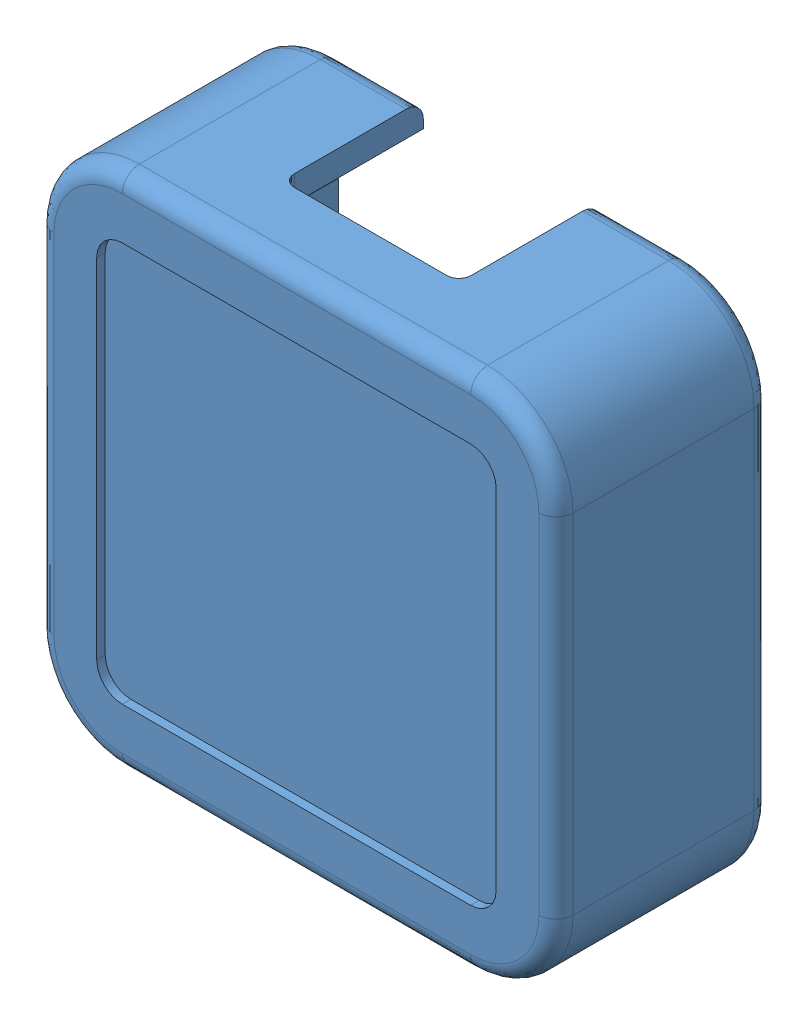
SolidWorks assembly enclosure-compatible module moulded 20x20, configuration Default. Lengths in mm.
Overall size (30.4 30.4 12.6).
5 component instances, 5 part files, 12 mates.
Components (placement in the parent):
- enclosure-compatible module 20x20-1: enclosure-compatible module 20x20 [Default] at (8.2244 14.4247 23.4545) size (27 28.5 1.62) (hidden)
- edge connector wall-1: edge connector wall [Default] at (8.2244 27.9247 23.4545) x (1 0 0) z (0 1 0) size (12.94 7.5 5.35) (hidden)
- enclosure end piece jacdac 20-1: enclosure end piece jacdac 20 [Default] at (8.2244 27.9247 23.4545) x (1 0 0) z (0 1 0) size (20 7.5 2) (hidden)
- enclosure end piece solid 20-1: enclosure end piece solid 20 [Default] at (8.2244 0.9247 25.0045) x (1 0 0) z (0 -1 0) size (20 7.5 2) (hidden)
- enclosure moulded 20x20-1: enclosure moulded 20x20 [Default] at (8.2244 27.9247 23.4545) x (1 0 0) z (0 1 0) size (30.4 12.6 30.4)
Mates (geometry in assembly coordinates):
- InPlace1: in place: plane of enclosure-compatible module 20x20-1 through (-5.2756 27.9247 25.0545) normal (0 1 0); plane of ? through (0 27.9247 0) normal (0 1 0); moOrthogonalPlaneRef_w of enclosure-compatible module 20x20-1 through (-5.2756 27.9247 25.0545) normal (0 1 0); plane of ? through (0 27.9247 0) normal (0 0 -1); plane of enclosure-compatible module 20x20-1 through (-5.2756 27.9247 25.0545) normal (0 1 0); plane of ? through (0 27.9247 0) normal (1 0 0); plane of enclosure-compatible module 20x20-1 through (-5.2756 27.9247 25.0545) normal (0 1 0); unknown of ?
- Coincident1: coincident: plane of enclosure-compatible module 20x20-1; plane of edge connector wall-1
- Coincident2: coincident: moOrthogonalPlaneRef_w of enclosure-compatible module 20x20-1 through (8.2244 27.9247 23.4545) normal (0 0 -1); plane of edge connector wall-1 through (8.2244 27.9247 23.4545) normal (0 0 -1)
- Coincident3: coincident: moOrthogonalPlaneRef_w of enclosure-compatible module 20x20-1 through (8.2244 27.9247 23.4545) normal (-1 0 0); plane of edge connector wall-1 through (8.2244 27.9247 23.4545) normal (1 0 0)
- InPlace2: in place: plane of enclosure-compatible module 20x20-1 through (-5.2756 27.9247 25.0545) normal (0 1 0); plane of ? through (0 27.9247 0) normal (0 1 0); plane of enclosure-compatible module 20x20-1 through (-5.2756 27.9247 25.0545) normal (0 1 0); plane of ? through (0 27.9247 0) normal (0 0 -1); plane of enclosure-compatible module 20x20-1 through (-5.2756 27.9247 25.0545) normal (0 1 0); plane of ? through (0 27.9247 0) normal (1 0 0); plane of enclosure-compatible module 20x20-1 through (-5.2756 27.9247 25.0545) normal (0 1 0); unknown of ?
- Coincident4: coincident: plane of enclosure-compatible module 20x20-1; plane of enclosure end piece jacdac 20-1
- Coincident5: coincident: moOrthogonalPlaneRef_w of enclosure-compatible module 20x20-1 through (8.2244 27.9247 23.4545) normal (0 0 -1); plane of enclosure end piece jacdac 20-1 through (8.2244 27.9247 23.4545) normal (0 0 -1)
- Coincident6: coincident: moOrthogonalPlaneRef_w of enclosure-compatible module 20x20-1 through (8.2244 27.9247 23.4545) normal (-1 0 0); plane of enclosure end piece jacdac 20-1 through (8.2244 27.9247 23.4545) normal (1 0 0)
- InPlace3: in place: plane of enclosure-compatible module 20x20-1 through (-5.2756 27.9247 25.0545) normal (0 1 0); plane of ? through (0 27.9247 0) normal (0 1 0); plane of enclosure-compatible module 20x20-1 through (-5.2756 27.9247 25.0545) normal (0 1 0); plane of ? through (0 27.9247 0) normal (0 0 -1); plane of enclosure-compatible module 20x20-1 through (-5.2756 27.9247 25.0545) normal (0 1 0); plane of ? through (0 27.9247 0) normal (1 0 0); plane of enclosure-compatible module 20x20-1 through (-5.2756 27.9247 25.0545) normal (0 1 0); unknown of ?
- Coincident1: coincident: plane of enclosure-compatible module 20x20-1; plane of enclosure moulded 20x20-1
- Coincident2: coincident: moOrthogonalPlaneRef_w of enclosure-compatible module 20x20-1 through (8.2244 27.9247 23.4545) normal (0 0 -1); plane of enclosure moulded 20x20-1 through (8.2244 27.9247 23.4545) normal (0 0 -1)
- Coincident3: coincident: moOrthogonalPlaneRef_w of enclosure-compatible module 20x20-1 through (8.2244 27.9247 23.4545) normal (-1 0 0); plane of enclosure moulded 20x20-1 through (8.2244 27.9247 23.4545) normal (1 0 0)
